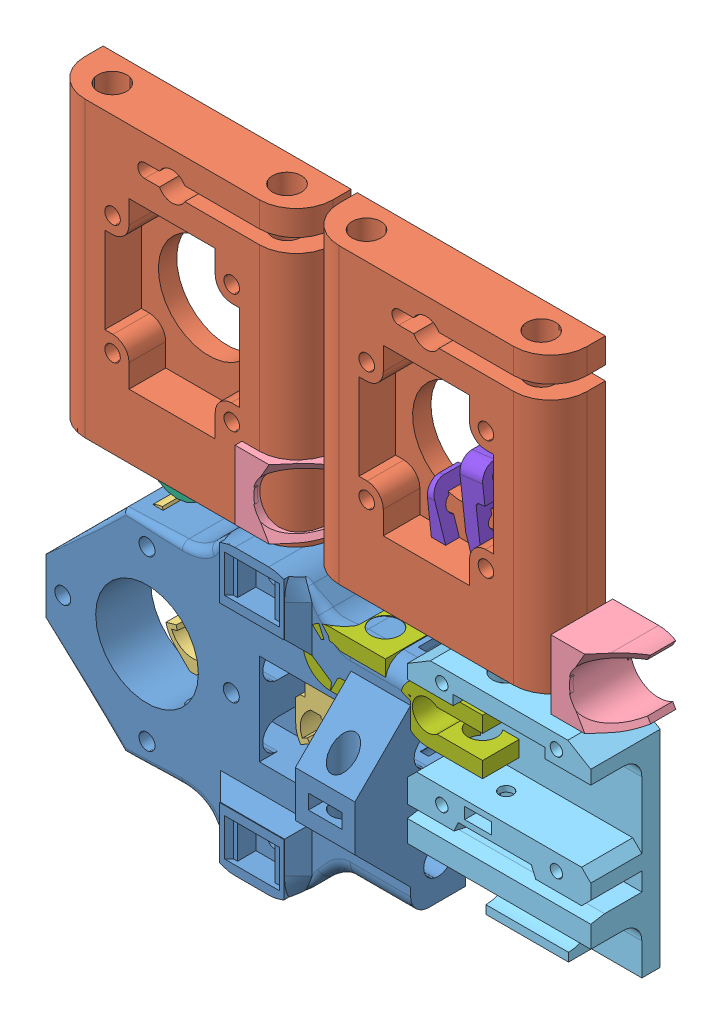
SolidWorks assembly up sheet1, configuration Default. Lengths in mm.
Overall size (130 130 24.15).
15 component instances, 8 part files, 16 mates.
Components (placement in the parent):
- x-motor-bracket 05-1: x-motor-bracket 05 [Default] at (2.6181 9.6138 0) size (79.5 62 24.15)
- z-motor-bracket 01-1: z-motor-bracket 01 [Default] at (57.1522 128.8049 12) x (0 -1 0) z (0 0 -1) size (64 54.1 12)
- z-motor-bracket 01-2: z-motor-bracket 01 [Default] at (112.5997 128.825 12) x (0 -1 0) z (0 0 -1) size (64 54.1 12)
- 6mm prusa bushing 01-1: 6mm prusa bushing 01 [Default] at (30.6692 35.9012 0) x (-0.705138 -0.70907 0) z (0 0 1) size (12 13.42 8)
- 6mm prusa bushing 01-2: 6mm prusa bushing 01 [Default] at (24.6942 50.3176 0) x (-0.664382 0.747393 0) z (0 0 1) size (12 13.42 8)
- 6mm prusa bushing 01-3: 6mm prusa bushing 01 [Default] at (59.0598 29.8108 0) x (0.999999 0.001082 0) z (0 0 1) size (12 13.42 8)
- bearing-holder 00-1: bearing-holder 00 [Default] at (55.3494 73.8059 13.5) x (0.999999 0.00154 0) z (0 0 -1) size (13.75 15 13.5)
- x-carriage 06-1: x-carriage 06 [Default] at (84.5596 25.5047 0) size (40 48 15.15)
- T2_5x16-y-idler-pulley 00-1: T2_5x16-y-idler-pulley 00 [Pulley-16-T2,5-16-2-Mekanex] at (27.1136 66.2129 0.1127) x (0 0 1) z (-1 0 0) size (7.98 14 14)
- T2_5x16-y-idler-pulley 00-2: T2_5x16-y-idler-pulley 00 [Pulley-16-T2,5-16-2-Mekanex] at (70.7975 67.7176 0.1127) x (0 0 1) z (-1 0 0) size (7.98 14 14)
- T2_5x16-y-idler-pulley 00-3: T2_5x16-y-idler-pulley 00 [Pulley-16-T2,5-16-2-Mekanex] at (42.1818 50.1386 0.1127) x (0 0 1) z (-1 0 0) size (7.98 14 14)
- bearing-holder 00-2: bearing-holder 00 [Default] at (124.2083 72.4379 13.5) x (0.999999 0.00154 0) z (0 0 -1) size (13.75 15 13.5)
- y-bar-clamp 00-1: y-bar-clamp 00 [Default] at (85.8097 49.7687 0) size (18 12 12)
- y-bar-clamp 00-2: y-bar-clamp 00 [Default] at (64.6216 49.7972 0) size (18 12 12)
- z-opto-holder 00-1: z-opto-holder 00 [Default] at (88.6711 74.7998 0) x (-0.119945 0.992781 0) z (0 0 1) size (29.5 13.07 7)
Mates (geometry in assembly coordinates):
- Coincident1: coincident aligned: plane of x-motor-bracket 05-1 through (2.6181 9.6138 0) normal (0 0 1); plane of assembly through (0 0 0) normal (0 0 1)
- Distance1: distance = 12 mm anti-aligned: plane of z-motor-bracket 01-1 through (57.1522 128.8049 12) normal (0 0 -1); plane of assembly through (0 0 0) normal (0 0 1)
- Parallel1: parallel anti-aligned: plane of z-motor-bracket 01-1; plane of assembly through (0 0 0) normal (1 0 0)
- Coincident4: coincident aligned: plane of 6mm prusa bushing 01-1 through (30.6692 35.9012 0) normal (0 0 1); plane of assembly through (0 0 0) normal (0 0 1)
- Coincident5: coincident aligned: plane of 6mm prusa bushing 01-2 through (24.6942 50.3176 0) normal (0 0 1); plane of assembly through (0 0 0) normal (0 0 1)
- Coincident8: coincident anti-aligned: plane of z-motor-bracket 01-2 through (58.4947 128.825 0) normal (0 0 -1); plane of assembly through (0 0 0) normal (0 0 1)
- Coincident9: coincident anti-aligned: plane of 6mm prusa bushing 01-3 through (59.0598 29.8108 0) normal (0 0 -1); plane of assembly through (0 0 0) normal (0 0 1)
- Coincident10: coincident anti-aligned: plane of bearing-holder 00-1 through (55.3494 73.8059 0) normal (0 0 -1); plane of assembly through (0 0 0) normal (0 0 1)
- Coincident11: coincident aligned: plane of x-carriage 06-1 through (84.5596 25.5047 0) normal (0 0 1); plane of assembly through (0 0 0) normal (0 0 1)
- Coincident12: coincident anti-aligned: plane of T2_5x16-y-idler-pulley 00-1 through (27.1136 73.0835 0) normal (0 0 -1); plane of assembly through (0 0 0) normal (0 0 1)
- Coincident13: coincident anti-aligned: plane of T2_5x16-y-idler-pulley 00-2 through (70.7975 74.5882 0) normal (0 0 -1); plane of assembly through (0 0 0) normal (0 0 1)
- Coincident14: coincident anti-aligned: plane of T2_5x16-y-idler-pulley 00-3 through (42.1818 57.0092 0) normal (0 0 -1); plane of assembly through (0 0 0) normal (0 0 1)
- Coincident15: coincident aligned: plane of bearing-holder 00-1 through (55.3494 73.8059 0) normal (0 0 -1); plane of bearing-holder 00-2 through (124.2083 72.4379 0) normal (0 0 -1)
- Coincident16: coincident anti-aligned: plane of y-bar-clamp 00-1 through (85.8097 49.7687 0) normal (0 0 -1); plane of assembly through (0 0 0) normal (0 0 1)
- Coincident17: coincident aligned: plane of y-bar-clamp 00-1 through (85.8097 49.7687 0) normal (0 0 -1); plane of y-bar-clamp 00-2 through (64.6216 49.7972 0) normal (0 0 -1)
- Coincident18: coincident anti-aligned: plane of z-opto-holder 00-1 through (88.6711 74.7998 0) normal (0 0 -1); plane of assembly through (0 0 0) normal (0 0 1)
